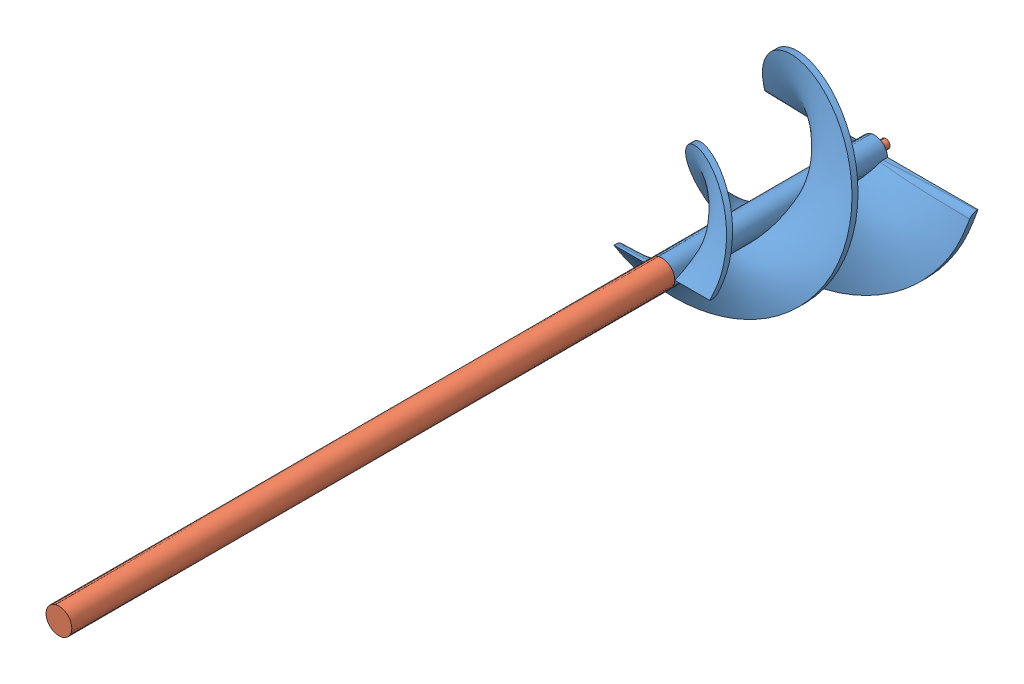
SolidWorks assembly Auger, configuration Default. Lengths in mm.
Overall size (76.48 66.77 304.8).
3 component instances, 2 part files, 6 mates.
Components (placement in the parent):
- 1-flute auger-1: 1-flute auger [Default] at (-20.8306 3.8317 -30.0765) size (67.09 57.28 78.42)
- 1-flute auger-2: 1-flute auger [Default] at (-20.8306 3.8317 -30.0765) x (-1 0 0) z (0 0 1) size (67.09 57.28 78.42)
- Auger spindle-1: Auger spindle [Default] at (-20.8306 3.8317 -34.204) x (0 1 0) z (1 0 0) size (9.53 304.8 9.53)
Mates (geometry in assembly coordinates):
- Concentric1: concentric: cylinder of 1-flute auger-1 through (-20.8306 3.8317 48.346) axis (0 0 -1) radius 1.5875; cylinder of 1-flute auger-2 through (-20.8306 3.8317 48.346) axis (0 0 -1) radius 1.5875
- Coincident1: coincident: plane of 1-flute auger-1 through (-20.8306 3.8317 48.346) normal (0 0 1); plane of 1-flute auger-2 through (-20.8306 3.8317 48.346) normal (0 0 1)
- Coincident2: coincident anti-aligned: line of 1-flute auger-1 through (17.2694 3.8317 -30.0765) axis (-1 0 0); line of 1-flute auger-2 through (-58.9306 3.8317 -30.0765) axis (1 0 0)
- Concentric2: concentric: cylinder of 1-flute auger-2 through (-20.8306 3.8317 48.346) axis (0 0 -1) radius 4.7625; cylinder of Auger spindle-1 through (-20.8306 3.8317 270.596) axis (0 0 1) radius 4.7625
- Coincident3: coincident: plane of 1-flute auger-2 through (-20.8306 3.8317 48.346) normal (0 0 1); plane of Auger spindle-1 through (-21.8341 5.0619 48.346) normal (0 0 -1)
- Coincident4: coincident anti-aligned: plane of 1-flute auger-2; plane of Auger spindle-1 through (-20.8306 3.8317 -34.204) normal (1 0 0)
